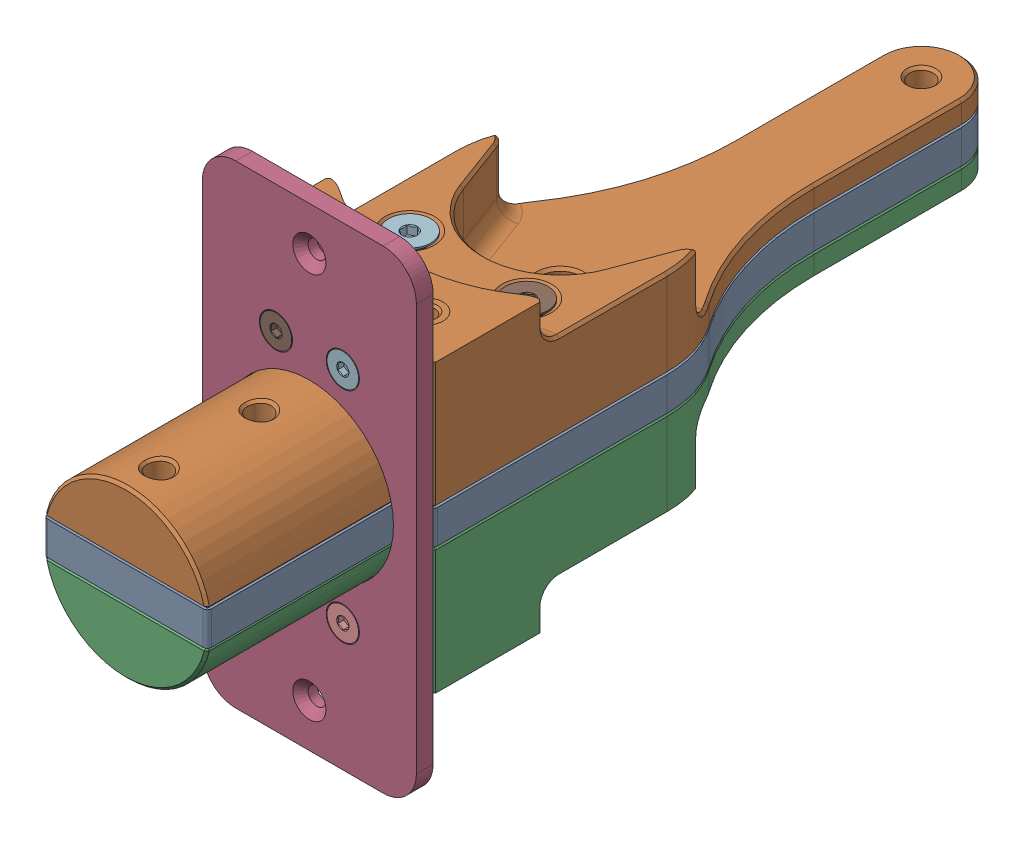
SolidWorks assembly Pivoting Assembly, configuration Default. Lengths in mm.
Overall size (42.82 89.97 158.75).
28 component instances, 10 part files, 0 mates.
Components (placement in the parent):
- Pivot Mid Plate-1: Pivot Mid Plate [Default] at origin size (40.64 6.35 158.75)
- Pivot Block A-1: Pivot Block A [Default] at origin size (41.73 24.41 158.75)
- Pivot Block B-1: Pivot Block B [Default] at origin size (41.73 24.41 158.75)
- Pivot Top Plate-1: Pivot Top Plate [Default] at origin size (40.64 89.97 3.17)
- 94180A331-1: 94180A331 [Default] at (-6.35 -20.8575 197.7644) size (5.56 5.56 3.8)
- 94180A331-2: 94180A331 [Default] at (6.35 -20.8575 197.7644) size (5.56 5.56 3.8)
- 94180A331-3: 94180A331 [Default] at (-6.35 20.8575 197.7644) size (5.56 5.56 3.8)
- 94180A331-4: 94180A331 [Default] at (6.35 20.8575 197.7644) size (5.56 5.56 3.8)
- 91294A130-1: 91294A130 [Default] at (-6.35 -20.8575 200.9394) size (6 6 10.12)
- 91294A130-2: 91294A130 [Default] at (6.35 -20.8575 200.9394) size (6 6 10.12)
- 91294A130-3: 91294A130 [Default] at (-6.35 20.8575 200.9394) size (6 6 10.12)
- 91294A130-4: 91294A130 [Default] at (6.35 20.8575 200.9394) size (6 6 10.12)
- 94180A351-1: 94180A351 [Default] at (-11.1125 -27.2075 189.8269) x (1 0 0) z (0 -1 0) size (6.35 6.35 4.7)
- 94180A351-2: 94180A351 [Default] at (11.1125 27.2075 189.8269) x (1 0 0) z (0 1 0) size (6.35 6.35 4.7)
- 93625A150-1: 93625A150 [Default] at (-11.1125 -3.175 189.8269) x (1 0 0) z (0 -1 0) size (7 8.08 5)
  - 93625A150_2-1: 93625A150_2 [Default] at origin size (7 8.08 5)
  - 93625A150-1: 93625A150 [Default] at origin size (6.53 6.53 0.53)
- 93625A150-2: 93625A150 [Default] at (11.1125 3.175 189.8269) x (1 0 0) z (0 1 0) size (7 8.08 5)
  - 93625A150_2-1: 93625A150_2 [Default] at origin size (7 8.08 5)
  - 93625A150-1: 93625A150 [Default] at origin size (6.53 6.53 0.53)
- 93625A150-3: 93625A150 [Default] at (-11.1125 -9.8438 170.7769) x (1 0 0) z (0 -1 0) size (7 8.08 5)
  - 93625A150_2-1: 93625A150_2 [Default] at origin size (7 8.08 5)
  - 93625A150-1: 93625A150 [Default] at origin size (6.53 6.53 0.53)
- 93625A150-4: 93625A150 [Default] at (11.1125 -9.8438 170.7769) x (1 0 0) z (0 -1 0) size (7 8.08 5)
  - 93625A150_2-1: 93625A150_2 [Default] at origin size (7 8.08 5)
  - 93625A150-1: 93625A150 [Default] at origin size (6.53 6.53 0.53)
- 92125A204-1: 92125A204 [Default] at (11.1125 19.8438 170.7769) x (1 0 0) z (0 1 0) size (8 8 35.14)
- 92125A204-2: 92125A204 [Default] at (-11.1125 19.8438 170.7769) x (1 0 0) z (0 1 0) size (8 8 35.14)
